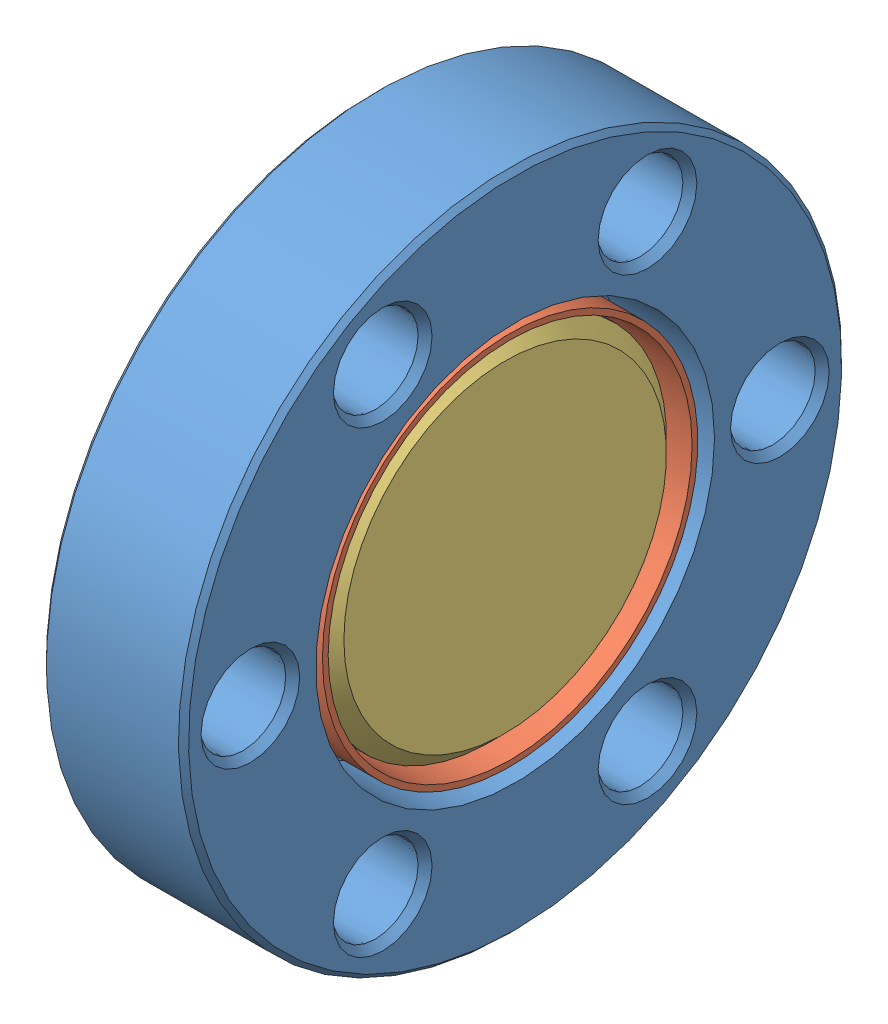
SolidWorks assembly 1.33 Viewport, configuration Default. Lengths in mm.
Overall size (7.24 33.78 33.78).
4 component instances, 3 part files, 0 mates.
Components (placement in the parent):
- 0784301N-1: 0784301N [Default] at origin size (7.24 33.78 33.78)
  - 0784101L-1: 0784101L [Default] at origin size (7.24 33.78 33.78)
  - 0194307B-1: 0194307B [Default] at (7.62 0 0) x (0 1 0) z (0 0 1) size (19.13 5.33 19.13)
- 1002201A-1: 1002201A [Default] at (4.191 0 0) x (0 0 -1) z (1 0 0) size (17.96 17.96 2.54)
